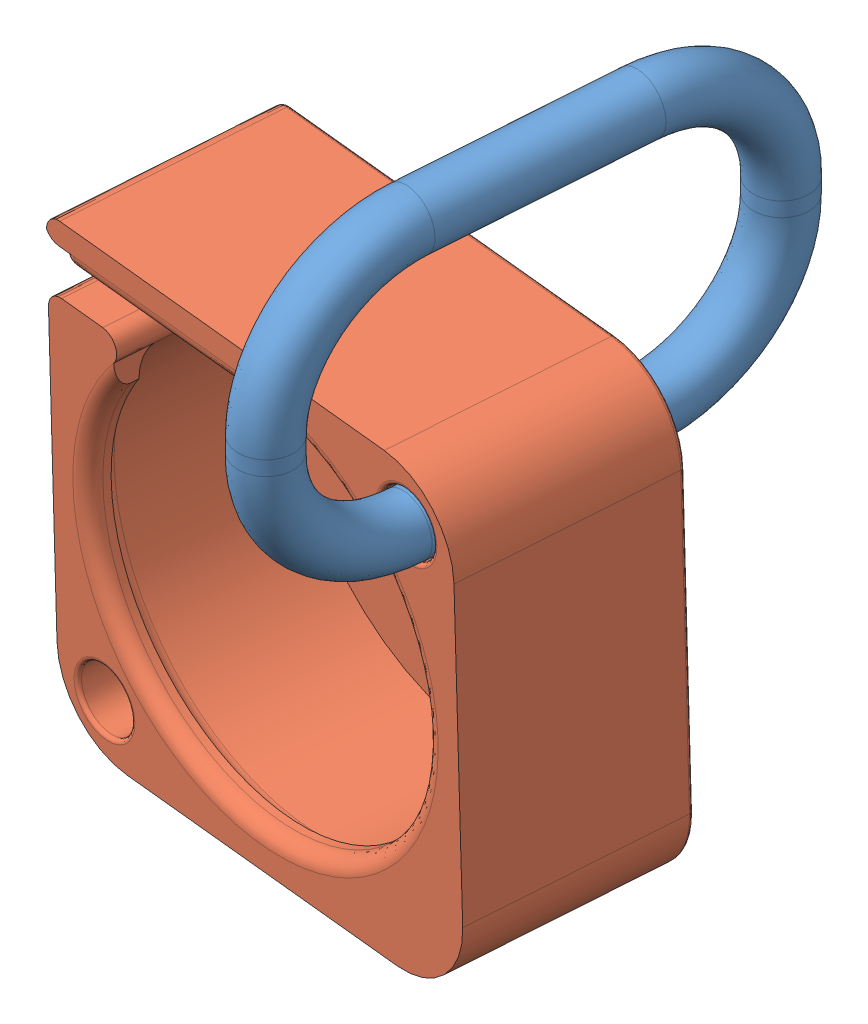
SolidWorks assembly RingAssemblage, configuration Défaut. Lengths in mm.
Overall size (31.59 47.41 35.94).
2 component instances, 2 part files, 2 mates.
Components (placement in the parent):
- Atache-1: Atache [Défaut] at (-1.886 7.7096 21.0517) x (0.09867 0.027578 -0.994738) z (0.994211 -0.045441 0.097358) size (35.05 22.05 3.8)
- enrouleur-1: enrouleur [Défaut] at (-27.3531 -0.9827 3.2052) x (0.995119 -0.001364 0.09867) z (-0.09867 -0.027578 0.994738) size (30 30 14.14)
Mates (geometry in assembly coordinates):
- Coaxiale1: concentric anti-aligned: circle of Atache-1; circle of enrouleur-1
- Coïncidente1: coincident anti-aligned: plane of Atache-1; plane of enrouleur-1 through (-23.7248 -26.3661 16.9354) normal (-0.09867 -0.027578 0.994738)
